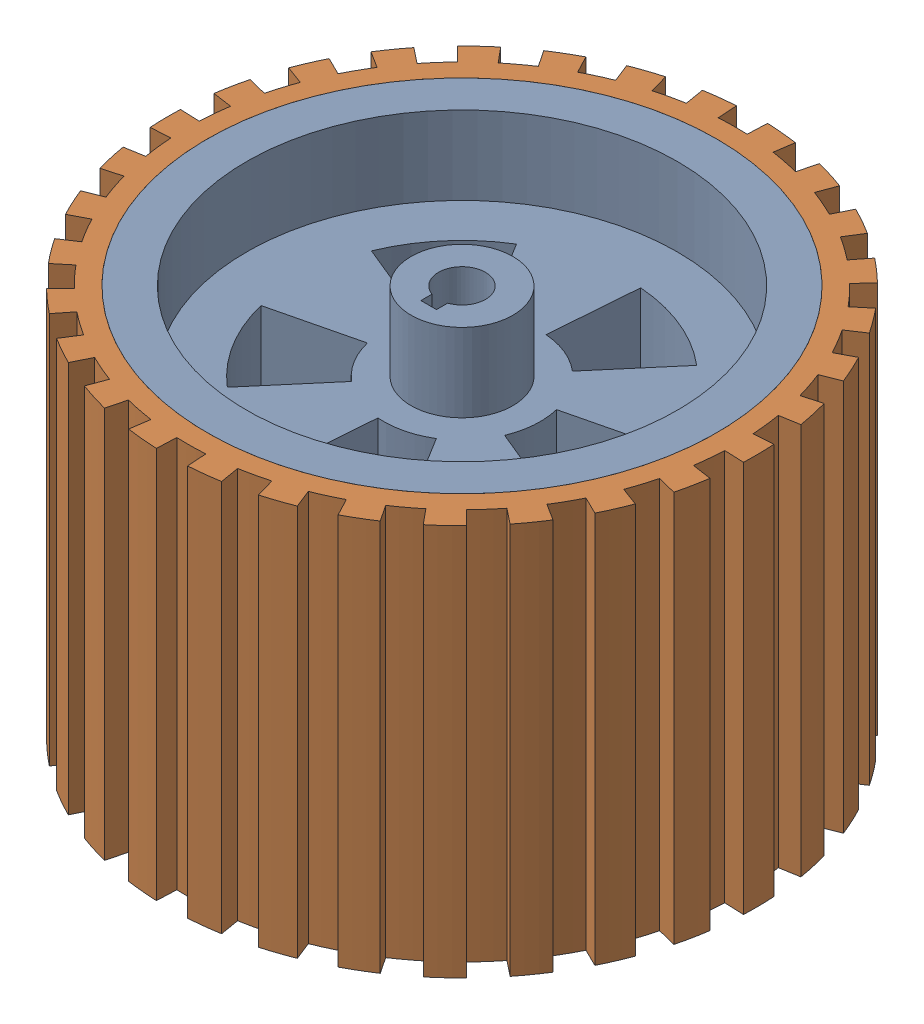
SolidWorks assembly Mirrorside wheel (rubber+rim), configuration Default. Lengths in mm.
Overall size (211.82 100 211.83).
2 component instances, 2 part files, 2 mates.
Components (placement in the parent):
- Mirrorside wheel rim-1: Mirrorside wheel rim [Default] at (68.1365 40.0161 -108.3416) size (130 100 130)
- Mirrorside wheel rubber-1: Mirrorside wheel rubber [Default] at (68.1365 40.0161 -108.3416) x (0.734903 0 -0.678172) z (0.678172 0 0.734903) size (149.8 100 150)
Mates (geometry in assembly coordinates):
- Coincident1: coincident aligned: circle of Mirrorside wheel rim-1; circle of Mirrorside wheel rubber-1
- Lock1: lock: unknown of Mirrorside wheel rim-1; unknown of Mirrorside wheel rubber-1
